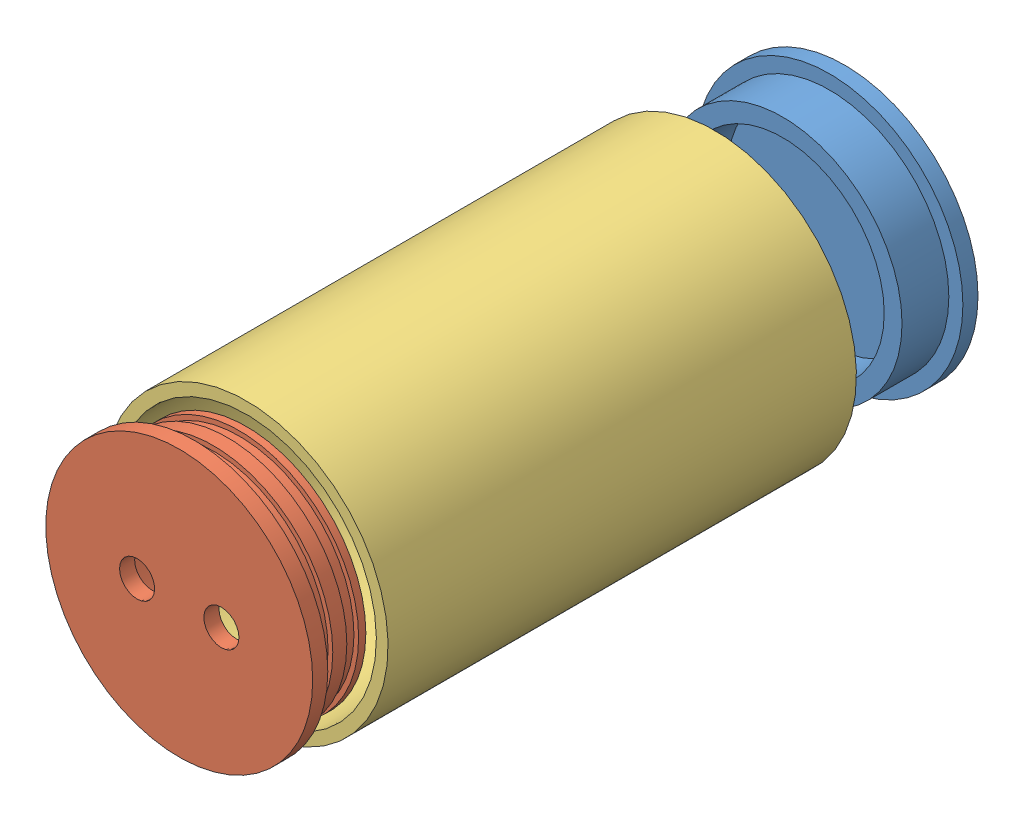
SolidWorks assembly Assem1, configuration Default. Lengths in mm.
Overall size (158.12 158.12 284.12).
3 component instances, 3 part files, 3 mates.
Components (placement in the parent):
- cap_fixed-1: cap_fixed [Default] at (74.9478 87.359 51.4777) size (114 114 26.45)
- cap_remove-1: cap_remove [Default] at (74.9478 138.359 314.8829) size (114 114 28.7)
- housing-1: housing [Default] at (74.9478 87.359 214.0405) x (-0.923728 -0.383049 0) z (0 0 -1) size (121 121 200)
Mates (geometry in assembly coordinates):
- Concentric2: concentric anti-aligned: cylinder of cap_fixed-1 through (74.9478 87.359 94.4648) axis (0 0 1) radius 51; cylinder of housing-1 through (74.9478 87.359 141.0928) axis (0 0 -1) radius 55.5
- Concentric6: concentric anti-aligned: cylinder of cap_remove-1 through (74.9478 87.359 321.3329) axis (0 0 1) radius 51; cylinder of housing-1 through (74.9478 87.359 141.0928) axis (0 0 -1) radius 55.5
- Concentric7: concentric anti-aligned: cylinder of cap_fixed-1 through (74.9478 87.359 94.4648) axis (0 0 1) radius 51; cylinder of housing-1 through (74.9478 87.359 141.0928) axis (0 0 -1) radius 55.5
